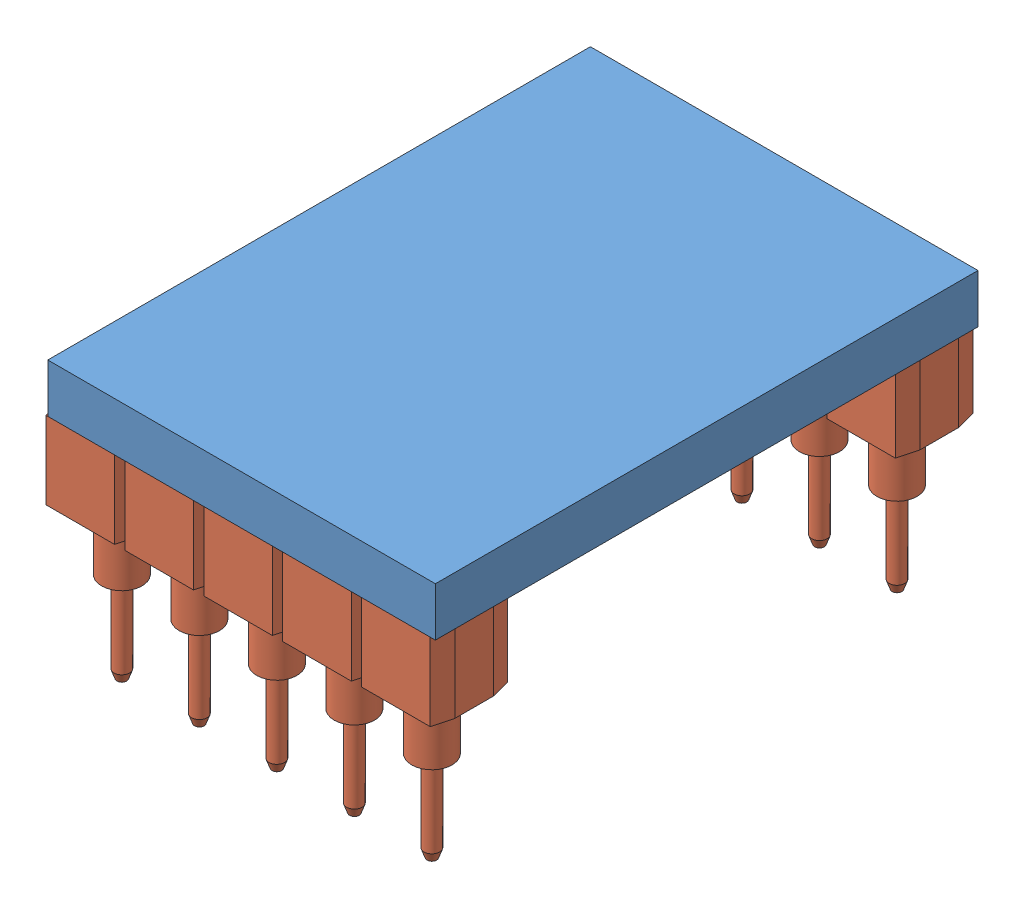
SolidWorks assembly Board, configuration Default. Lengths in mm.
Overall size (12.93 9.09 17.78).
3 component instances, 2 part files, 6 mates.
Components (placement in the parent):
- Part3^Board-1: Part3^Board [Default] at (-13.5721 128.5531 9.1116) x (1 0 0) z (0 1 0) size (12.7 17.78 1.6) (virtual)
- SS-105-G-2-1: SS-105-G-2 [Default] at (-13.9147 126.0131 9.2412) size (12.93 7.62 2.54)
- SS-105-G-2-2: SS-105-G-2 [Default] at (-13.9147 126.0131 24.4812) size (12.93 7.62 2.54)
Mates (geometry in assembly coordinates):
- Coincident8: coincident: plane of SS-105-G-2-1 through (-20.3123 128.6482 9.2412) normal (0 1 0); plane of SS-105-G-2-2 through (-20.3123 128.6482 24.4812) normal (0 1 0)
- Coincident9: coincident: plane of SS-105-G-2-1 through (-7.3837 128.6482 9.8762) normal (1 0 0); plane of SS-105-G-2-2 through (-7.3837 128.6482 25.1162) normal (1 0 0)
- Coincident10: coincident: plane of Part3^Board-1 through (-13.5721 128.5531 9.1451) normal (0 -1 0); plane of SS-105-G-2-1 through (-20.379 128.5531 9.2412) normal (0 1 0)
- Distance2: distance = 15.24 mm: line of SS-105-G-2-1 through (-7.6206 128.5531 7.9712) axis (-1 0 0); line of SS-105-G-2-2 through (-7.6206 128.5531 23.2112) axis (-1 0 0)
- Coincident12: coincident: plane of Part3^Board-1 through (-7.4504 130.1531 7.9712) normal (1 0 0); plane of SS-105-G-2-1 through (-7.4504 128.5531 9.8762) normal (1 0 0)
- Coincident13: coincident aligned: plane of Part3^Board-1 through (-7.4504 130.1531 7.9712) normal (0 0 -1); plane of SS-105-G-2-1 through (-12.792 128.5531 7.9712) normal (0 0 -1)
